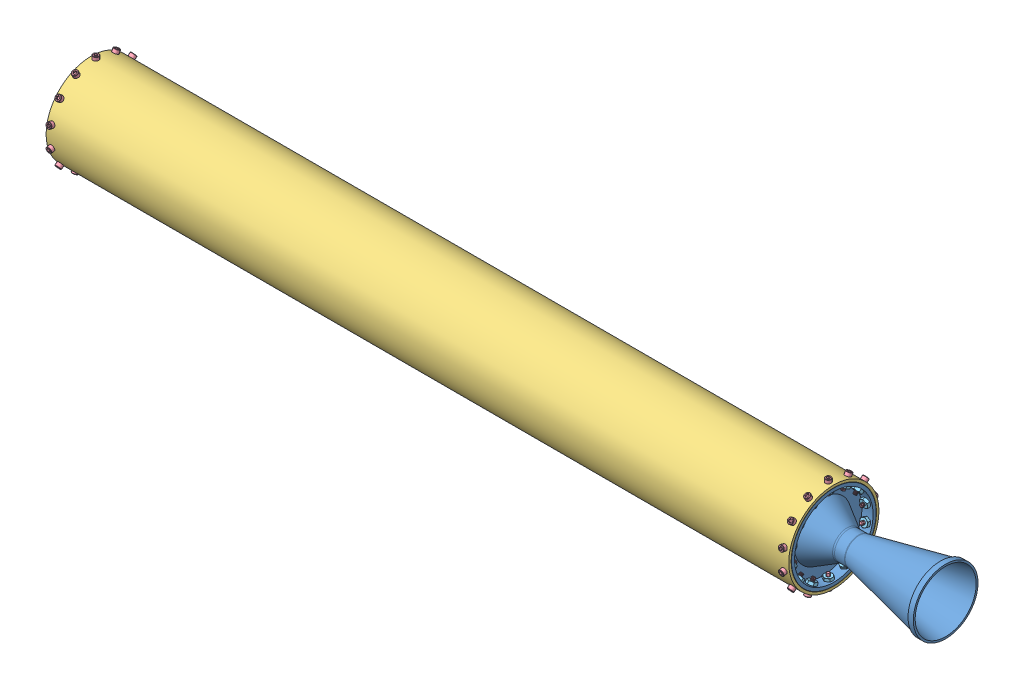
SolidWorks assembly Nakka Lambda Montado, configuration Valor predeterminado. Lengths in mm.
Overall size (702.9 79.69 79.01).
59 component instances, 5 part files, 121 mates.
Components (placement in the parent):
- Nakka Lambda Nozzle Revolucionado-1: Nakka Lambda Nozzle Revolucionado [Valor predeterminado] at (371.1003 28.4053 113.4672) size (113.47 69.52 69.52)
- Nakka Lambda Pressure Bulkhead Revolucionado-1: Nakka Lambda Pressure Bulkhead Revolucionado [Valor predeterminado] at (-252.1521 28.4053 113.4672) size (20.07 69.58 69.58)
- Nakka Lambda Corpo Revolucionado-2: Nakka Lambda Corpo Revolucionado [Valor predeterminado] at (16.4106 28.4053 113.4672) size (610 74 74)
- socket head cap screw_ai440-0375rosca-17: socket head cap screw_ai440-0375rosca [HX-SHCS 0.112-40x0.375x0.375-S] at (336.2613 37.2716 152.313) x (0 -0.222521 -0.974928) z (0.974928 -0.216942 0.049516) size (12.37 4.65 4.65)
- socket head cap screw_ai440-0375rosca-29: socket head cap screw_ai440-0375rosca [HX-SHCS 0.112-40x0.375x0.375-S] at (336.2613 19.539 74.6214) x (0 0.222521 0.974928) z (-0.472254 0.859362 -0.196144) size (12.37 4.65 4.65)
- socket head cap screw_ai440-0375rosca-31: socket head cap screw_ai440-0375rosca [HX-SHCS 0.112-40x0.375x0.375-S] at (336.2613 37.2716 74.6214) x (0 -0.222521 0.974928) z (-0.974928 0.216942 0.049516) size (12.37 4.65 4.65)
- socket head cap screw_ai440-0375rosca-32: socket head cap screw_ai440-0375rosca [HX-SHCS 0.112-40x0.375x0.375-S] at (336.2613 53.2482 82.3153) x (0 -0.62349 0.781831) z (-0.781831 0.487464 0.38874) size (12.37 4.65 4.65)
- socket head cap screw_ai440-0375rosca-33: socket head cap screw_ai440-0375rosca [HX-SHCS 0.112-40x0.375x0.375-S] at (336.2613 64.3043 96.1792) x (0 -0.900969 0.433884) z (-0.433884 0.390916 0.811745) size (12.37 4.65 4.65)
- socket head cap screw_ai440-0375rosca-34: socket head cap screw_ai440-0375rosca [HX-SHCS 0.112-40x0.375x0.375-S] at (336.2613 68.2501 113.4672) x (0 -1 0) z (0 0 1) size (12.37 4.65 4.65)
- socket head cap screw_ai440-0375rosca-35: socket head cap screw_ai440-0375rosca [HX-SHCS 0.112-40x0.375x0.375-S] at (336.2613 64.3043 130.7552) x (0 -0.900969 -0.433884) z (0.433884 -0.390916 0.811745) size (12.37 4.65 4.65)
- socket head cap screw_ai440-0375rosca-36: socket head cap screw_ai440-0375rosca [HX-SHCS 0.112-40x0.375x0.375-S] at (336.2613 53.2482 144.6191) x (0 -0.62349 -0.781831) z (0.781831 -0.487464 0.38874) size (12.37 4.65 4.65)
- socket head cap screw_ai440-0375rosca-37: socket head cap screw_ai440-0375rosca [HX-SHCS 0.112-40x0.375x0.375-S] at (336.2613 19.539 152.313) x (0 0.222521 -0.974928) z (-0.164533 0.961641 0.219488) size (12.37 4.65 4.65)
- socket head cap screw_ai440-0375rosca-38: socket head cap screw_ai440-0375rosca [HX-SHCS 0.112-40x0.375x0.375-S] at (336.2613 3.5625 144.6191) x (0 0.62349 -0.781831) z (0.781831 0.487464 0.38874) size (12.37 4.65 4.65)
- socket head cap screw_ai440-0375rosca-39: socket head cap screw_ai440-0375rosca [HX-SHCS 0.112-40x0.375x0.375-S] at (336.2613 -11.4395 113.4672) x (0 1 0) z (0.020592 0 0.999788) size (12.37 4.65 4.65)
- socket head cap screw_ai440-0375rosca-40: socket head cap screw_ai440-0375rosca [HX-SHCS 0.112-40x0.375x0.375-S] at (336.2613 -7.4936 130.7552) x (0 0.900969 -0.433884) z (0.712028 0.304652 0.632616) size (12.37 4.65 4.65)
- socket head cap screw_ai440-0375rosca-41: socket head cap screw_ai440-0375rosca [HX-SHCS 0.112-40x0.375x0.375-S] at (336.2613 3.5625 82.3153) x (0 0.62349 0.781831) z (-0.781831 -0.487464 0.38874) size (12.37 4.65 4.65)
- socket head cap screw_ai440-0375rosca-42: socket head cap screw_ai440-0375rosca [HX-SHCS 0.112-40x0.375x0.375-S] at (336.2613 -7.4936 96.1792) x (0 0.900969 0.433884) z (-0.433884 -0.390916 0.811745) size (12.37 4.65 4.65)
- socket head cap screw_ai440-0375rosca-44: socket head cap screw_ai440-0375rosca [HX-SHCS 0.112-40x0.375x0.375-S] at (-265.3567 -11.4395 113.4672) x (0 1 0) z (-0.975169 0 0.221462) size (12.37 4.65 4.65)
- socket head cap screw_ai440-0375rosca-45: socket head cap screw_ai440-0375rosca [HX-SHCS 0.112-40x0.375x0.375-S] at (-265.3567 37.2716 152.313) x (0 -0.222521 -0.974928) z (0.974928 -0.216942 0.049516) size (12.37 4.65 4.65)
- socket head cap screw_ai440-0375rosca-46: socket head cap screw_ai440-0375rosca [HX-SHCS 0.112-40x0.375x0.375-S] at (-265.3567 -7.4936 130.7552) x (0 0.900969 -0.433884) z (0.433884 0.390916 0.811745) size (12.37 4.65 4.65)
- socket head cap screw_ai440-0375rosca-47: socket head cap screw_ai440-0375rosca [HX-SHCS 0.112-40x0.375x0.375-S] at (-265.3567 3.5625 144.6191) x (0 0.62349 -0.781831) z (0.223701 -0.762018 -0.607689) size (12.37 4.65 4.65)
- socket head cap screw_ai440-0375rosca-48: socket head cap screw_ai440-0375rosca [HX-SHCS 0.112-40x0.375x0.375-S] at (-265.3567 19.539 152.313) x (0 0.222521 -0.974928) z (-0.073092 0.97232 0.221926) size (12.37 4.65 4.65)
- socket head cap screw_ai440-0375rosca-49: socket head cap screw_ai440-0375rosca [HX-SHCS 0.112-40x0.375x0.375-S] at (-265.3567 68.2501 113.4672) x (0 -1 0) z (0.796271 0 0.60494) size (12.37 4.65 4.65)
- socket head cap screw_ai440-0375rosca-50: socket head cap screw_ai440-0375rosca [HX-SHCS 0.112-40x0.375x0.375-S] at (-265.3567 53.2482 82.3153) x (0 -0.62349 0.781831) z (0.988386 0.11881 0.094748) size (12.37 4.65 4.65)
- socket head cap screw_ai440-0375rosca-58: socket head cap screw_ai440-0375rosca [HX-SHCS 0.112-40x0.375x0.375-S] at (-265.3567 64.3043 130.7552) x (0 -0.900969 -0.433884) z (-0.063272 0.433014 -0.899164) size (12.37 4.65 4.65)
- socket head cap screw_ai440-0375rosca-59: socket head cap screw_ai440-0375rosca [HX-SHCS 0.112-40x0.375x0.375-S] at (-265.3567 64.3043 96.1792) x (0 -0.900969 0.433884) z (-0.99848 0.023912 0.049653) size (12.37 4.65 4.65)
- socket head cap screw_ai440-0375rosca-60: socket head cap screw_ai440-0375rosca [HX-SHCS 0.112-40x0.375x0.375-S] at (-265.3567 53.2482 144.6191) x (0 -0.62349 -0.781831) z (0.332471 0.737356 -0.588022) size (12.37 4.65 4.65)
- socket head cap screw_ai440-0375rosca-61: socket head cap screw_ai440-0375rosca [HX-SHCS 0.112-40x0.375x0.375-S] at (-265.3567 37.2716 74.6214) x (0 -0.222521 0.974928) z (-0.29064 -0.932843 -0.212915) size (12.37 4.65 4.65)
- socket head cap screw_ai440-0375rosca-62: socket head cap screw_ai440-0375rosca [HX-SHCS 0.112-40x0.375x0.375-S] at (-265.3567 19.539 74.6214) x (0 0.222521 0.974928) z (-0.974928 -0.216942 0.049516) size (12.37 4.65 4.65)
- socket head cap screw_ai440-0375rosca-63: socket head cap screw_ai440-0375rosca [HX-SHCS 0.112-40x0.375x0.375-S] at (-265.3567 3.5625 82.3153) x (0 0.62349 0.781831) z (-0.79157 0.47776 -0.381001) size (12.37 4.65 4.65)
- socket head cap screw_ai440-0375rosca-64: socket head cap screw_ai440-0375rosca [HX-SHCS 0.112-40x0.375x0.375-S] at (-265.3567 -7.4936 96.1792) x (0 0.900969 0.433884) z (-0.918204 -0.171864 0.35688) size (12.37 4.65 4.65)
- machine screw nut hex_ai440rosca-4: machine screw nut hex_ai440rosca [MSHXNUT 0.112-40-D-S] at (-265.3567 -1.2873 113.4672) x (0.229119 0 -0.973398) z (0 1 0) size (6.35 7.33 2.49)
- machine screw nut hex_ai440rosca-5: machine screw nut hex_ai440rosca [MSHXNUT 0.112-40-D-S] at (-265.3567 55.1575 100.584) x (1 0 0) z (0 -0.900969 0.433884) size (6.35 7.33 2.49)
- machine screw nut hex_ai440rosca-6: machine screw nut hex_ai440rosca [MSHXNUT 0.112-40-D-S] at (-265.3567 35.0126 84.519) x (1 0 0) z (0 -0.222521 0.974928) size (6.35 7.33 2.49)
- machine screw nut hex_ai440rosca-7: machine screw nut hex_ai440rosca [MSHXNUT 0.112-40-D-S] at (-265.3567 46.9184 90.2526) x (1 0 0) z (0 -0.62349 0.781831) size (6.35 7.33 2.49)
- machine screw nut hex_ai440rosca-8: machine screw nut hex_ai440rosca [MSHXNUT 0.112-40-D-S] at (336.2613 -0.6238 127.4469) x (1 0 0) z (0 -0.900969 0.433884) size (6.35 7.33 2.49)
- machine screw nut hex_ai440rosca-9: machine screw nut hex_ai440rosca [MSHXNUT 0.112-40-D-S] at (336.2613 48.4941 138.6577) x (0.474899 0.688043 -0.548696) z (0 0.62349 0.781831) size (6.35 7.33 2.49)
- machine screw nut hex_ai440rosca-10: machine screw nut hex_ai440rosca [MSHXNUT 0.112-40-D-S] at (336.2613 55.1918 100.5675) x (1 0 0) z (0 -0.900969 0.433884) size (6.35 7.33 2.49)
- machine screw nut hex_ai440rosca-11: machine screw nut hex_ai440rosca [MSHXNUT 0.112-40-D-S] at (-265.3567 35.5665 144.8421) x (0.912832 -0.398097 0.090863) z (0 0.222521 0.974928) size (6.35 7.33 2.49)
- machine screw nut hex_ai440rosca-12: machine screw nut hex_ai440rosca [MSHXNUT 0.112-40-D-S] at (-265.3567 9.8923 90.2526) x (1 0 0) z (0 0.62349 0.781831) size (6.35 7.33 2.49)
- machine screw nut hex_ai440rosca-13: machine screw nut hex_ai440rosca [MSHXNUT 0.112-40-D-S] at (336.2613 21.2357 144.8793) x (0.004219 -0.974919 -0.222519) z (0 -0.222521 0.974928) size (6.35 7.33 2.49)
- machine screw nut hex_ai440rosca-14: machine screw nut hex_ai440rosca [MSHXNUT 0.112-40-D-S] at (-265.3567 48.4704 138.6279) x (0.052973 -0.780734 0.622614) z (0 0.62349 0.781831) size (6.35 7.33 2.49)
- machine screw nut hex_ai440rosca-15: machine screw nut hex_ai440rosca [MSHXNUT 0.112-40-D-S] at (336.2613 35.5749 144.8793) x (-0.28602 0.934199 -0.213225) z (0 0.222521 0.974928) size (6.35 7.33 2.49)
- machine screw nut hex_ai440rosca-16: machine screw nut hex_ai440rosca [MSHXNUT 0.112-40-D-S] at (-265.3567 8.3403 138.6279) x (0.580628 -0.636543 -0.507626) z (0 -0.62349 0.781831) size (6.35 7.33 2.49)
- machine screw nut hex_ai440rosca-17: machine screw nut hex_ai440rosca [MSHXNUT 0.112-40-D-S] at (336.2613 9.8686 90.2228) x (1 0 0) z (0 0.62349 0.781831) size (6.35 7.33 2.49)
- machine screw nut hex_ai440rosca-18: machine screw nut hex_ai440rosca [MSHXNUT 0.112-40-D-S] at (336.2613 8.3166 138.6577) x (0.295846 -0.746833 -0.59558) z (0 -0.62349 0.781831) size (6.35 7.33 2.49)
- machine screw nut hex_ai440rosca-19: machine screw nut hex_ai440rosca [MSHXNUT 0.112-40-D-S] at (336.2613 58.136 113.4672) x (0.879271 0 -0.476321) z (0 -1 0) size (6.35 7.33 2.49)
- machine screw nut hex_ai440rosca-20: machine screw nut hex_ai440rosca [MSHXNUT 0.112-40-D-S] at (336.2613 1.6189 100.5675) x (1 0 0) z (0 0.900969 0.433884) size (6.35 7.33 2.49)
- machine screw nut hex_ai440rosca-21: machine screw nut hex_ai440rosca [MSHXNUT 0.112-40-D-S] at (336.2613 57.4345 127.4469) x (-0.189494 -0.426023 0.884645) z (0 0.900969 0.433884) size (6.35 7.33 2.49)
- machine screw nut hex_ai440rosca-22: machine screw nut hex_ai440rosca [MSHXNUT 0.112-40-D-S] at (336.2613 -1.3254 113.4672) x (1 0 0) z (0 1 0) size (6.35 7.33 2.49)
- machine screw nut hex_ai440rosca-23: machine screw nut hex_ai440rosca [MSHXNUT 0.112-40-D-S] at (336.2613 46.9421 90.2228) x (1 0 0) z (0 -0.62349 0.781831) size (6.35 7.33 2.49)
- machine screw nut hex_ai440rosca-24: machine screw nut hex_ai440rosca [MSHXNUT 0.112-40-D-S] at (336.2613 21.7896 84.4819) x (1 0 0) z (0 0.222521 0.974928) size (6.35 7.33 2.49)
- machine screw nut hex_ai440rosca-25: machine screw nut hex_ai440rosca [MSHXNUT 0.112-40-D-S] at (336.2613 35.021 84.4819) x (1 0 0) z (0 -0.222521 0.974928) size (6.35 7.33 2.49)
- machine screw nut hex_ai440rosca-26: machine screw nut hex_ai440rosca [MSHXNUT 0.112-40-D-S] at (-265.3567 58.0979 113.4672) x (1 0 0) z (0 -1 0) size (6.35 7.33 2.49)
- machine screw nut hex_ai440rosca-27: machine screw nut hex_ai440rosca [MSHXNUT 0.112-40-D-S] at (-265.3567 21.2442 144.8421) x (-0.080248 -0.971784 -0.221803) z (0 -0.222521 0.974928) size (6.35 7.33 2.49)
- machine screw nut hex_ai440rosca-28: machine screw nut hex_ai440rosca [MSHXNUT 0.112-40-D-S] at (-265.3567 21.7981 84.519) x (1 0 0) z (0 0.222521 0.974928) size (6.35 7.33 2.49)
- machine screw nut hex_ai440rosca-29: machine screw nut hex_ai440rosca [MSHXNUT 0.112-40-D-S] at (-265.3567 -0.5895 127.4303) x (-0.019937 -0.433797 -0.90079) z (0 -0.900969 0.433884) size (6.35 7.33 2.49)
- machine screw nut hex_ai440rosca-33: machine screw nut hex_ai440rosca [MSHXNUT 0.112-40-D-S] at (-265.3567 57.4001 127.4303) x (0.879954 -0.20612 0.428013) z (0 0.900969 0.433884) size (6.35 7.33 2.49)
- machine screw nut hex_ai440rosca-32: machine screw nut hex_ai440rosca [MSHXNUT 0.112-40-D-S] at (-265.3567 1.6532 100.584) x (1 0 0) z (0 0.900969 0.433884) size (6.35 7.33 2.49)
Mates (geometry in assembly coordinates):
- Concêntrico2: concentric aligned: circle of Nakka Lambda Nozzle Revolucionado-1; circle of Nakka Lambda Corpo Revolucionado-2
- Concêntrico7: concentric aligned: cylinder of Nakka Lambda Pressure Bulkhead Revolucionado-1 through (-265.3567 -2.8779 128.5324) axis (0 -0.900969 0.433884) radius 1.1303; cylinder of Nakka Lambda Corpo Revolucionado-2 through (-265.3567 -4.9305 129.5209) axis (0 -0.900969 0.433884) radius 1.1303
- Concêntrico22: concentric aligned: cylinder of Nakka Lambda Corpo Revolucionado-2 through (336.2613 36.6386 149.5395) axis (0 0.222521 0.974928) radius 1.1303; cylinder of socket head cap screw_ai440-0375rosca-17 through (336.2613 44.3367 183.267) axis (0 0.222521 0.974928) radius 1.4224
- Concêntrico25: concentric aligned: cylinder of Nakka Lambda Nozzle Revolucionado-1 through (336.2613 50.0778 140.6436) axis (0 0.62349 0.781831) radius 1.1303; cylinder of Nakka Lambda Corpo Revolucionado-2 through (336.2613 51.4745 142.3949) axis (0 0.62349 0.781831) radius 1.1303
- Concêntrico26: concentric aligned: cylinder of Nakka Lambda Nozzle Revolucionado-1 through (336.2613 36.1402 147.3556) axis (0 0.222521 0.974928) radius 1.1303; cylinder of Nakka Lambda Corpo Revolucionado-2 through (336.2613 36.6386 149.5395) axis (0 0.222521 0.974928) radius 1.1303
- Concêntrico27: concentric aligned: circle of Nakka Lambda Nozzle Revolucionado-1; circle of Nakka Lambda Corpo Revolucionado-2
- Tangente12: tangent anti-aligned: cylinder of Nakka Lambda Corpo Revolucionado-2 through (-269.1667 28.4053 113.4672) axis (-1 0 0) radius 37; plane of socket head cap screw_ai440-0375rosca-17 through (336.7785 38.8476 149.0353) normal (0 -0.222521 -0.974928)
- Concêntrico34: concentric aligned: cylinder of Nakka Lambda Nozzle Revolucionado-1 through (336.2613 -2.9122 98.3854) axis (0 -0.900969 -0.433884) radius 1.1303; cylinder of Nakka Lambda Corpo Revolucionado-2 through (336.2613 -4.9305 97.4135) axis (0 -0.900969 -0.433884) radius 1.1303
- Concêntrico54: concentric aligned: cylinder of Nakka Lambda Nozzle Revolucionado-1 through (336.2613 50.0778 140.6436) axis (0 0.62349 0.781831) radius 1.1303; cylinder of Nakka Lambda Corpo Revolucionado-2 through (336.2613 51.4745 142.3949) axis (0 0.62349 0.781831) radius 1.1303
- Concêntrico57: concentric aligned: cylinder of Nakka Lambda Corpo Revolucionado-2 through (336.2613 20.1721 77.3948) axis (0 -0.222521 -0.974928) radius 1.1303; cylinder of socket head cap screw_ai440-0375rosca-29 through (336.2613 12.474 43.6674) axis (0 -0.222521 -0.974928) radius 1.4224
- Tangente14: tangent anti-aligned: cylinder of Nakka Lambda Corpo Revolucionado-2 through (-269.1667 28.4053 113.4672) axis (-1 0 0) radius 37; plane of socket head cap screw_ai440-0375rosca-29 through (338.3099 21.2421 77.1506) normal (0 0.222521 0.974928)
- Concêntrico60: concentric aligned: cylinder of Nakka Lambda Corpo Revolucionado-2 through (336.2613 36.6386 77.3948) axis (0 0.222521 -0.974928) radius 1.1303; cylinder of socket head cap screw_ai440-0375rosca-31 through (336.2613 44.3367 43.6674) axis (0 0.222521 -0.974928) radius 1.4224
- Tangente15: tangent anti-aligned: cylinder of Nakka Lambda Corpo Revolucionado-2 through (-269.1667 28.4053 113.4672) axis (-1 0 0) radius 37; plane of socket head cap screw_ai440-0375rosca-31 through (336.7785 38.8476 77.899) normal (0 -0.222521 0.974928)
- Concêntrico62: concentric aligned: cylinder of Nakka Lambda Corpo Revolucionado-2 through (336.2613 51.4745 84.5394) axis (0 0.62349 -0.781831) radius 1.1303; cylinder of socket head cap screw_ai440-0375rosca-32 through (336.2613 73.044 57.4921) axis (0 0.62349 -0.781831) radius 1.4224
- Tangente17: tangent anti-aligned: cylinder of Nakka Lambda Corpo Revolucionado-2 through (-269.1667 28.4053 113.4672) axis (-1 0 0) radius 37; plane of socket head cap screw_ai440-0375rosca-32 through (337.7104 52.8951 85.6723) normal (0 -0.62349 0.781831)
- Concêntrico64: concentric aligned: cylinder of Nakka Lambda Corpo Revolucionado-2 through (336.2613 61.7412 97.4135) axis (0 0.900969 -0.433884) radius 1.1303; cylinder of socket head cap screw_ai440-0375rosca-33 through (336.2613 92.91 82.4034) axis (0 0.900969 -0.433884) radius 1.4224
- Tangente18: tangent anti-aligned: cylinder of Nakka Lambda Corpo Revolucionado-2 through (-269.1667 28.4053 113.4672) axis (-1 0 0) radius 37; plane of socket head cap screw_ai440-0375rosca-33 through (338.3553 62.1787 98.322) normal (0 -0.900969 0.433884)
- Concêntrico66: concentric aligned: cylinder of Nakka Lambda Corpo Revolucionado-2 through (336.2613 65.4053 113.4672) axis (0 1 0) radius 1.1303; cylinder of socket head cap screw_ai440-0375rosca-34 through (336.2613 100.0001 113.4672) axis (0 1 0) radius 1.4224
- Tangente19: tangent anti-aligned: cylinder of Nakka Lambda Corpo Revolucionado-2 through (-269.1667 28.4053 113.4672) axis (-1 0 0) radius 37; plane of socket head cap screw_ai440-0375rosca-34 through (338.5854 65.4053 113.4672) normal (0 -1 0)
- Concêntrico68: concentric aligned: cylinder of Nakka Lambda Corpo Revolucionado-2 through (336.2613 61.7412 129.5209) axis (0 0.900969 0.433884) radius 1.1303; cylinder of socket head cap screw_ai440-0375rosca-35 through (336.2613 92.91 144.531) axis (0 0.900969 0.433884) radius 1.4224
- Tangente20: tangent anti-aligned: cylinder of Nakka Lambda Corpo Revolucionado-2 through (-269.1667 28.4053 113.4672) axis (-1 0 0) radius 37; plane of socket head cap screw_ai440-0375rosca-35 through (338.3553 62.1787 128.6124) normal (0 -0.900969 -0.433884)
- Concêntrico70: concentric aligned: cylinder of Nakka Lambda Corpo Revolucionado-2 through (336.2613 51.4745 142.3949) axis (0 0.62349 0.781831) radius 1.1303; cylinder of socket head cap screw_ai440-0375rosca-36 through (336.2613 73.044 169.4422) axis (0 0.62349 0.781831) radius 1.4224
- Tangente21: tangent anti-aligned: cylinder of Nakka Lambda Corpo Revolucionado-2 through (-269.1667 28.4053 113.4672) axis (-1 0 0) radius 37; plane of socket head cap screw_ai440-0375rosca-36 through (337.7104 52.8951 141.262) normal (0 -0.62349 -0.781831)
- Concêntrico72: concentric aligned: cylinder of Nakka Lambda Corpo Revolucionado-2 through (336.2613 20.1721 149.5395) axis (0 -0.222521 0.974928) radius 1.1303; cylinder of socket head cap screw_ai440-0375rosca-37 through (336.2613 12.474 183.267) axis (0 -0.222521 0.974928) radius 1.4224
- Tangente22: tangent anti-aligned: cylinder of Nakka Lambda Corpo Revolucionado-2 through (-269.1667 28.4053 113.4672) axis (-1 0 0) radius 37; plane of socket head cap screw_ai440-0375rosca-37 through (333.9689 19.7993 149.4544) normal (0 0.222521 -0.974928)
- Concêntrico76: concentric aligned: cylinder of Nakka Lambda Corpo Revolucionado-2 through (336.2613 5.3362 142.3949) axis (0 -0.62349 0.781831) radius 1.1303; cylinder of socket head cap screw_ai440-0375rosca-38 through (336.2613 -16.2333 169.4422) axis (0 -0.62349 0.781831) radius 1.4224
- Tangente23: tangent anti-aligned: cylinder of Nakka Lambda Corpo Revolucionado-2 through (-269.1667 28.4053 113.4672) axis (-1 0 0) radius 37; plane of socket head cap screw_ai440-0375rosca-38 through (334.8123 6.7569 143.5279) normal (0 0.62349 -0.781831)
- Concêntrico78: concentric aligned: cylinder of Nakka Lambda Corpo Revolucionado-2 through (336.2613 -4.9305 129.5209) axis (0 -0.900969 0.433884) radius 1.1303; cylinder of socket head cap screw_ai440-0375rosca-40 through (336.2613 -36.0993 144.531) axis (0 -0.900969 0.433884) radius 1.4224
- Tangente24: tangent anti-aligned: cylinder of Nakka Lambda Corpo Revolucionado-2 through (-269.1667 28.4053 113.4672) axis (-1 0 0) radius 37; plane of socket head cap screw_ai440-0375rosca-40 through (334.6294 -4.2125 131.0118) normal (0 0.900969 -0.433884)
- Concêntrico80: concentric aligned: cylinder of Nakka Lambda Corpo Revolucionado-2 through (336.2613 -8.5947 113.4672) axis (0 -1 0) radius 1.1303; cylinder of socket head cap screw_ai440-0375rosca-39 through (336.2613 -43.1895 113.4672) axis (0 -1 0) radius 1.4224
- Tangente25: tangent anti-aligned: cylinder of Nakka Lambda Corpo Revolucionado-2 through (-269.1667 28.4053 113.4672) axis (-1 0 0) radius 37; plane of socket head cap screw_ai440-0375rosca-39 through (333.9377 -8.5947 113.515) normal (0 1 0)
- Concêntrico81: concentric aligned: circle of Nakka Lambda Pressure Bulkhead Revolucionado-1; circle of Nakka Lambda Corpo Revolucionado-2
- Concêntrico83: concentric aligned: cylinder of Nakka Lambda Corpo Revolucionado-2 through (336.2613 -4.9305 97.4135) axis (0 -0.900969 -0.433884) radius 1.1303; cylinder of socket head cap screw_ai440-0375rosca-42 through (336.2613 -36.0993 82.4034) axis (0 -0.900969 -0.433884) radius 1.4224
- Tangente26: tangent anti-aligned: cylinder of Nakka Lambda Corpo Revolucionado-2 through (-269.1667 28.4053 113.4672) axis (-1 0 0) radius 37; plane of socket head cap screw_ai440-0375rosca-42 through (334.1674 -4.493 96.505) normal (0 0.900969 0.433884)
- Concêntrico85: concentric aligned: cylinder of Nakka Lambda Corpo Revolucionado-2 through (336.2613 5.3362 84.5394) axis (0 -0.62349 -0.781831) radius 1.1303; cylinder of socket head cap screw_ai440-0375rosca-41 through (336.2613 -16.2333 57.4921) axis (0 -0.62349 -0.781831) radius 1.4224
- Tangente27: tangent anti-aligned: cylinder of Nakka Lambda Corpo Revolucionado-2 through (-269.1667 28.4053 113.4672) axis (-1 0 0) radius 37; plane of socket head cap screw_ai440-0375rosca-41 through (334.8123 6.7569 83.4065) normal (0 0.62349 0.781831)
- Concêntrico86: concentric aligned: cylinder of Nakka Lambda Pressure Bulkhead Revolucionado-1 through (-265.3567 20.679 79.6159) axis (0 -0.222521 -0.974928) radius 1.1303; cylinder of Nakka Lambda Corpo Revolucionado-2 through (-265.3567 20.1721 77.3948) axis (0 -0.222521 -0.974928) radius 1.1303
- Concêntrico88: concentric aligned: cylinder of Nakka Lambda Corpo Revolucionado-2 through (-265.3567 -8.5947 113.4672) axis (0 -1 0) radius 1.1303; cylinder of socket head cap screw_ai440-0375rosca-44 through (-265.3567 -43.1895 113.4672) axis (0 -1 0) radius 1.4224
- Tangente28: tangent anti-aligned: cylinder of Nakka Lambda Corpo Revolucionado-2 through (-269.1667 28.4053 113.4672) axis (-1 0 0) radius 37; plane of socket head cap screw_ai440-0375rosca-44 through (-265.8714 -8.5947 111.2008) normal (0 1 0)
- Concêntrico90: concentric aligned: cylinder of Nakka Lambda Corpo Revolucionado-2 through (-265.3567 -4.9305 129.5209) axis (0 -0.900969 0.433884) radius 1.1303; cylinder of socket head cap screw_ai440-0375rosca-46 through (-265.3567 -36.0993 144.531) axis (0 -0.900969 0.433884) radius 1.4224
- Tangente29: tangent anti-aligned: cylinder of Nakka Lambda Corpo Revolucionado-2 through (-269.1667 28.4053 113.4672) axis (-1 0 0) radius 37; plane of socket head cap screw_ai440-0375rosca-46 through (-267.4506 -4.493 130.4294) normal (0 0.900969 -0.433884)
- Concêntrico92: concentric aligned: cylinder of Nakka Lambda Corpo Revolucionado-2 through (-265.3567 5.3362 142.3949) axis (0 -0.62349 0.781831) radius 1.1303; cylinder of socket head cap screw_ai440-0375rosca-47 through (-265.3567 -16.2333 169.4422) axis (0 -0.62349 0.781831) radius 1.4224
- Tangente30: tangent anti-aligned: cylinder of Nakka Lambda Corpo Revolucionado-2 through (-269.1667 28.4053 113.4672) axis (-1 0 0) radius 37; plane of socket head cap screw_ai440-0375rosca-47 through (-263.0915 5.7427 142.7191) normal (0 0.62349 -0.781831)
- Concêntrico94: concentric aligned: cylinder of Nakka Lambda Corpo Revolucionado-2 through (-265.3567 20.1721 149.5395) axis (0 -0.222521 0.974928) radius 1.1303; cylinder of socket head cap screw_ai440-0375rosca-48 through (-265.3567 12.474 183.267) axis (0 -0.222521 0.974928) radius 1.4224
- Tangente31: tangent anti-aligned: cylinder of Nakka Lambda Corpo Revolucionado-2 through (-269.1667 28.4053 113.4672) axis (-1 0 0) radius 37; plane of socket head cap screw_ai440-0375rosca-48 through (-267.6746 20.0065 149.5017) normal (0 0.222521 -0.974928)
- Concêntrico96: concentric aligned: cylinder of Nakka Lambda Corpo Revolucionado-2 through (-265.3567 36.6386 149.5395) axis (0 0.222521 0.974928) radius 1.1303; cylinder of socket head cap screw_ai440-0375rosca-45 through (-265.3567 44.3367 183.267) axis (0 0.222521 0.974928) radius 1.4224
- Tangente32: tangent anti-aligned: cylinder of Nakka Lambda Corpo Revolucionado-2 through (-269.1667 28.4053 113.4672) axis (-1 0 0) radius 37; plane of socket head cap screw_ai440-0375rosca-45 through (-264.8395 38.8476 149.0353) normal (0 -0.222521 -0.974928)
- Concêntrico98: concentric aligned: cylinder of Nakka Lambda Corpo Revolucionado-2 through (-265.3567 51.4745 142.3949) axis (0 0.62349 0.781831) radius 1.1303; cylinder of socket head cap screw_ai440-0375rosca-60 through (-265.3567 73.044 169.4422) axis (0 0.62349 0.781831) radius 1.4224
- Tangente33: tangent anti-aligned: cylinder of Nakka Lambda Corpo Revolucionado-2 through (-269.1667 28.4053 113.4672) axis (-1 0 0) radius 37; plane of socket head cap screw_ai440-0375rosca-60 through (-267.5486 52.0786 141.9132) normal (0 -0.62349 -0.781831)
- Concêntrico100: concentric aligned: cylinder of Nakka Lambda Corpo Revolucionado-2 through (-265.3567 61.7412 129.5209) axis (0 0.900969 0.433884) radius 1.1303; cylinder of socket head cap screw_ai440-0375rosca-58 through (-265.3567 92.91 144.531) axis (0 0.900969 0.433884) radius 1.4224
- Tangente34: tangent anti-aligned: cylinder of Nakka Lambda Corpo Revolucionado-2 through (-269.1667 28.4053 113.4672) axis (-1 0 0) radius 37; plane of socket head cap screw_ai440-0375rosca-58 through (-267.6761 61.6774 129.6534) normal (0 -0.900969 -0.433884)
- Concêntrico102: concentric aligned: cylinder of Nakka Lambda Corpo Revolucionado-2 through (-265.3567 65.4053 113.4672) axis (0 1 0) radius 1.1303; cylinder of socket head cap screw_ai440-0375rosca-49 through (-265.3567 100.0001 113.4672) axis (0 1 0) radius 1.4224
- Tangente35: tangent anti-aligned: cylinder of Nakka Lambda Corpo Revolucionado-2 through (-269.1667 28.4053 113.4672) axis (-1 0 0) radius 37; plane of socket head cap screw_ai440-0375rosca-49 through (-263.9507 65.4053 111.6166) normal (0 -1 0)
- Concêntrico104: concentric aligned: cylinder of Nakka Lambda Corpo Revolucionado-2 through (-265.3567 61.7412 97.4135) axis (0 0.900969 -0.433884) radius 1.1303; cylinder of socket head cap screw_ai440-0375rosca-59 through (-265.3567 92.91 82.4034) axis (0 0.900969 -0.433884) radius 1.4224
- Tangente36: tangent anti-aligned: cylinder of Nakka Lambda Corpo Revolucionado-2 through (-269.1667 28.4053 113.4672) axis (-1 0 0) radius 37; plane of socket head cap screw_ai440-0375rosca-59 through (-265.2286 62.7481 99.5042) normal (0 -0.900969 0.433884)
- Concêntrico106: concentric aligned: cylinder of Nakka Lambda Corpo Revolucionado-2 through (-265.3567 51.4745 84.5394) axis (0 0.62349 -0.781831) radius 1.1303; cylinder of socket head cap screw_ai440-0375rosca-50 through (-265.3567 73.044 57.4921) axis (0 0.62349 -0.781831) radius 1.4224
- Tangente37: tangent anti-aligned: cylinder of Nakka Lambda Corpo Revolucionado-2 through (-269.1667 28.4053 113.4672) axis (-1 0 0) radius 37; plane of socket head cap screw_ai440-0375rosca-50 through (-265.0035 49.6785 83.1072) normal (0 -0.62349 0.781831)
- Concêntrico108: concentric aligned: cylinder of Nakka Lambda Corpo Revolucionado-2 through (-265.3567 36.6386 77.3948) axis (0 0.222521 -0.974928) radius 1.1303; cylinder of socket head cap screw_ai440-0375rosca-61 through (-265.3567 44.3367 43.6674) axis (0 0.222521 -0.974928) radius 1.4224
- Tangente38: tangent anti-aligned: cylinder of Nakka Lambda Corpo Revolucionado-2 through (-269.1667 28.4053 113.4672) axis (-1 0 0) radius 37; plane of socket head cap screw_ai440-0375rosca-61 through (-267.5805 37.2972 77.5452) normal (0 -0.222521 0.974928)
- Concêntrico110: concentric aligned: cylinder of Nakka Lambda Corpo Revolucionado-2 through (-265.3567 20.1721 77.3948) axis (0 -0.222521 -0.974928) radius 1.1303; cylinder of socket head cap screw_ai440-0375rosca-62 through (-265.3567 12.474 43.6674) axis (0 -0.222521 -0.974928) radius 1.4224
- Tangente39: tangent anti-aligned: cylinder of Nakka Lambda Corpo Revolucionado-2 through (-269.1667 28.4053 113.4672) axis (-1 0 0) radius 37; plane of socket head cap screw_ai440-0375rosca-62 through (-265.8738 22.3811 76.8907) normal (0 0.222521 0.974928)
- Concêntrico112: concentric aligned: cylinder of Nakka Lambda Corpo Revolucionado-2 through (-265.3567 5.3362 84.5394) axis (0 -0.62349 -0.781831) radius 1.1303; cylinder of socket head cap screw_ai440-0375rosca-63 through (-265.3567 -16.2333 57.4921) axis (0 -0.62349 -0.781831) radius 1.4224
- Tangente40: tangent anti-aligned: cylinder of Nakka Lambda Corpo Revolucionado-2 through (-269.1667 28.4053 113.4672) axis (-1 0 0) radius 37; plane of socket head cap screw_ai440-0375rosca-63 through (-263.9365 6.7745 83.3924) normal (0 0.62349 0.781831)
- Concêntrico114: concentric aligned: cylinder of Nakka Lambda Corpo Revolucionado-2 through (-265.3567 -4.9305 97.4135) axis (0 -0.900969 -0.433884) radius 1.1303; cylinder of socket head cap screw_ai440-0375rosca-64 through (-265.3567 -36.0993 82.4034) axis (0 -0.900969 -0.433884) radius 1.4224
- Tangente42: tangent anti-aligned: cylinder of Nakka Lambda Corpo Revolucionado-2 through (-269.1667 28.4053 113.4672) axis (-1 0 0) radius 37; plane of socket head cap screw_ai440-0375rosca-64 through (-266.2773 -4.0046 95.4908) normal (0 0.900969 0.433884)
- Concêntrico117: concentric anti-aligned: cylinder of socket head cap screw_ai440-0375rosca-31 through (336.2613 44.3367 43.6674) axis (0 0.222521 -0.974928) radius 1.4224; cylinder of machine screw nut hex_ai440rosca-25 through (336.2613 35.5749 82.0551) axis (0 -0.222521 0.974928) radius 1.1303
- Tangente46: tangent aligned: cylinder of Nakka Lambda Nozzle Revolucionado-1 through (319.2433 28.4053 113.4672) axis (-1 0 0) radius 32.2199; plane of machine screw nut hex_ai440rosca-25 through (336.2613 39.1492 82.8709) normal (0 0.222521 -0.974928)
- Concêntrico118: concentric anti-aligned: cylinder of socket head cap screw_ai440-0375rosca-32 through (336.2613 73.044 57.4921) axis (0 0.62349 -0.781831) radius 1.4224; cylinder of machine screw nut hex_ai440rosca-23 through (336.2613 48.4941 88.2766) axis (0 -0.62349 0.781831) radius 1.1303
- Tangente47: tangent aligned: cylinder of Nakka Lambda Nozzle Revolucionado-1 through (319.2433 28.4053 113.4672) axis (-1 0 0) radius 32.2199; plane of machine screw nut hex_ai440rosca-23 through (336.2613 51.3605 90.5625) normal (0 0.62349 -0.781831)
- Concêntrico119: concentric anti-aligned: cylinder of socket head cap screw_ai440-0375rosca-29 through (336.2613 12.474 43.6674) axis (0 -0.222521 -0.974928) radius 1.4224; cylinder of machine screw nut hex_ai440rosca-24 through (336.2613 21.2357 82.0551) axis (0 0.222521 0.974928) radius 1.1303
- Tangente48: tangent aligned: cylinder of Nakka Lambda Nozzle Revolucionado-1 through (319.2433 28.4053 113.4672) axis (-1 0 0) radius 32.2199; plane of machine screw nut hex_ai440rosca-24 through (336.2613 24.81 81.2393) normal (0 -0.222521 -0.974928)
- Concêntrico120: concentric anti-aligned: cylinder of socket head cap screw_ai440-0375rosca-33 through (336.2613 92.91 82.4034) axis (0 0.900969 -0.433884) radius 1.4224; cylinder of machine screw nut hex_ai440rosca-10 through (336.2613 57.4345 99.4875) axis (0 -0.900969 0.433884) radius 1.1303
- Tangente49: tangent aligned: cylinder of Nakka Lambda Nozzle Revolucionado-1 through (319.2433 28.4053 113.4672) axis (-1 0 0) radius 32.2199; plane of machine screw nut hex_ai440rosca-10 through (336.2613 59.0252 102.7906) normal (0 0.900969 -0.433884)
- Concêntrico122: concentric anti-aligned: cylinder of socket head cap screw_ai440-0375rosca-39 through (336.2613 -43.1895 113.4672) axis (0 -1 0) radius 1.4224; cylinder of machine screw nut hex_ai440rosca-22 through (336.2613 -3.8146 113.4672) axis (0 1 0) radius 1.1303
- Tangente52: tangent aligned: cylinder of Nakka Lambda Nozzle Revolucionado-1 through (319.2433 28.4053 113.4672) axis (-1 0 0) radius 32.2199; plane of machine screw nut hex_ai440rosca-22 through (336.2613 -3.8146 109.801) normal (0 -1 0)
- Concêntrico123: concentric anti-aligned: cylinder of socket head cap screw_ai440-0375rosca-42 through (336.2613 -36.0993 82.4034) axis (0 -0.900969 -0.433884) radius 1.4224; cylinder of machine screw nut hex_ai440rosca-20 through (336.2613 -0.6238 99.4875) axis (0 0.900969 0.433884) radius 1.1303
- Tangente53: tangent aligned: cylinder of Nakka Lambda Nozzle Revolucionado-1 through (319.2433 28.4053 113.4672) axis (-1 0 0) radius 32.2199; plane of machine screw nut hex_ai440rosca-20 through (336.2613 0.9669 96.1844) normal (0 -0.900969 -0.433884)
- Concêntrico127: concentric aligned: cylinder of socket head cap screw_ai440-0375rosca-40 through (336.2613 -36.0993 144.531) axis (0 -0.900969 0.433884) radius 1.4224; cylinder of machine screw nut hex_ai440rosca-8 through (336.2613 1.6189 126.3668) axis (0 -0.900969 0.433884) radius 1.1303
- Tangente55: tangent aligned: cylinder of Nakka Lambda Nozzle Revolucionado-1 through (319.2433 28.4053 113.4672) axis (-1 0 0) radius 32.2199; plane of machine screw nut hex_ai440rosca-8 through (336.2613 0.9669 130.75) normal (0 -0.900969 0.433884)
- Concêntrico128: concentric anti-aligned: cylinder of socket head cap screw_ai440-0375rosca-34 through (336.2613 100.0001 113.4672) axis (0 1 0) radius 1.4224; cylinder of machine screw nut hex_ai440rosca-19 through (336.2613 60.6252 113.4672) axis (0 -1 0) radius 1.1303
- Tangente57: tangent aligned: cylinder of Nakka Lambda Nozzle Revolucionado-1 through (319.2433 28.4053 113.4672) axis (-1 0 0) radius 32.2199; plane of machine screw nut hex_ai440rosca-19 through (338.0076 60.6252 116.6907) normal (0 1 0)
- Concêntrico129: concentric aligned: cylinder of socket head cap screw_ai440-0375rosca-38 through (336.2613 -16.2333 169.4422) axis (0 -0.62349 0.781831) radius 1.4224; cylinder of machine screw nut hex_ai440rosca-18 through (336.2613 9.8686 136.7116) axis (0 -0.62349 0.781831) radius 1.1303
- Tangente58: tangent aligned: cylinder of Nakka Lambda Nozzle Revolucionado-1 through (319.2433 28.4053 113.4672) axis (-1 0 0) radius 32.2199; plane of machine screw nut hex_ai440rosca-18 through (339.7634 9.1646 139.334) normal (0 -0.62349 0.781831)
- Concêntrico130: concentric aligned: cylinder of socket head cap screw_ai440-0375rosca-37 through (336.2613 12.474 183.267) axis (0 -0.222521 0.974928) radius 1.4224; cylinder of machine screw nut hex_ai440rosca-13 through (336.2613 21.7896 142.4525) axis (0 -0.222521 0.974928) radius 1.1303
- Tangente59: tangent aligned: cylinder of Nakka Lambda Nozzle Revolucionado-1 through (319.2433 28.4053 113.4672) axis (-1 0 0) radius 32.2199; plane of machine screw nut hex_ai440rosca-13 through (339.9275 21.2508 144.8827) normal (0 -0.222521 0.974928)
- Concêntrico131: concentric anti-aligned: cylinder of socket head cap screw_ai440-0375rosca-41 through (336.2613 -16.2333 57.4921) axis (0 -0.62349 -0.781831) radius 1.4224; cylinder of machine screw nut hex_ai440rosca-17 through (336.2613 8.3166 88.2766) axis (0 0.62349 0.781831) radius 1.1303
- Tangente60: tangent aligned: cylinder of Nakka Lambda Nozzle Revolucionado-1 through (319.2433 28.4053 113.4672) axis (-1 0 0) radius 32.2199; plane of machine screw nut hex_ai440rosca-17 through (336.2613 11.1829 85.9908) normal (0 -0.62349 -0.781831)
- Concêntrico132: concentric aligned: cylinder of socket head cap screw_ai440-0375rosca-17 through (336.2613 44.3367 183.267) axis (0 0.222521 0.974928) radius 1.4224; cylinder of machine screw nut hex_ai440rosca-15 through (336.2613 35.021 142.4525) axis (0 0.222521 0.974928) radius 1.1303
- Tangente61: tangent aligned: cylinder of Nakka Lambda Nozzle Revolucionado-1 through (319.2433 28.4053 113.4672) axis (-1 0 0) radius 32.2199; plane of machine screw nut hex_ai440rosca-15 through (332.7483 34.5526 145.1126) normal (0 0.222521 0.974928)
- Concêntrico133: concentric aligned: cylinder of socket head cap screw_ai440-0375rosca-35 through (336.2613 92.91 144.531) axis (0 0.900969 0.433884) radius 1.4224; cylinder of machine screw nut hex_ai440rosca-21 through (336.2613 55.1918 126.3668) axis (0 0.900969 0.433884) radius 1.1303
- Tangente62: tangent aligned: cylinder of Nakka Lambda Nozzle Revolucionado-1 through (319.2433 28.4053 113.4672) axis (-1 0 0) radius 32.2199; plane of machine screw nut hex_ai440rosca-21 through (339.8611 57.133 128.0728) normal (0 0.900969 0.433884)
- Concêntrico134: concentric aligned: cylinder of socket head cap screw_ai440-0375rosca-36 through (336.2613 73.044 169.4422) axis (0 0.62349 0.781831) radius 1.4224; cylinder of machine screw nut hex_ai440rosca-9 through (336.2613 46.9421 136.7116) axis (0 0.62349 0.781831) radius 1.1303
- Tangente63: tangent aligned: cylinder of Nakka Lambda Nozzle Revolucionado-1 through (319.2433 28.4053 113.4672) axis (-1 0 0) radius 32.2199; plane of machine screw nut hex_ai440rosca-9 through (333.0349 49.8553 137.5722) normal (0 0.62349 0.781831)
- Concêntrico135: concentric anti-aligned: cylinder of socket head cap screw_ai440-0375rosca-62 through (-265.3567 12.474 43.6674) axis (0 -0.222521 -0.974928) radius 1.4224; cylinder of machine screw nut hex_ai440rosca-28 through (-265.3567 21.2442 82.0922) axis (0 0.222521 0.974928) radius 1.1303
- Tangente64: tangent aligned: cylinder of Nakka Lambda Pressure Bulkhead Revolucionado-1 through (-263.6543 28.4053 113.4672) axis (-1 0 0) radius 32.1818; plane of machine screw nut hex_ai440rosca-28 through (-265.3567 24.8185 81.2764) normal (0 -0.222521 -0.974928)
- Concêntrico136: concentric anti-aligned: cylinder of socket head cap screw_ai440-0375rosca-63 through (-265.3567 -16.2333 57.4921) axis (0 -0.62349 -0.781831) radius 1.4224; cylinder of machine screw nut hex_ai440rosca-12 through (-265.3567 8.3403 88.3064) axis (0 0.62349 0.781831) radius 1.1303
- Tangente65: tangent aligned: cylinder of Nakka Lambda Pressure Bulkhead Revolucionado-1 through (-263.6543 28.4053 113.4672) axis (-1 0 0) radius 32.1818; plane of machine screw nut hex_ai440rosca-12 through (-265.3567 11.2067 86.0206) normal (0 -0.62349 -0.781831)
- Concêntrico137: concentric anti-aligned: cylinder of socket head cap screw_ai440-0375rosca-61 through (-265.3567 44.3367 43.6674) axis (0 0.222521 -0.974928) radius 1.4224; cylinder of machine screw nut hex_ai440rosca-6 through (-265.3567 35.5665 82.0922) axis (0 -0.222521 0.974928) radius 1.1303
- Tangente67: tangent aligned: cylinder of Nakka Lambda Pressure Bulkhead Revolucionado-1 through (-263.6543 28.4053 113.4672) axis (-1 0 0) radius 32.1818; plane of machine screw nut hex_ai440rosca-6 through (-265.3567 39.1407 82.908) normal (0 0.222521 -0.974928)
- Concêntrico138: concentric anti-aligned: cylinder of socket head cap screw_ai440-0375rosca-50 through (-265.3567 73.044 57.4921) axis (0 0.62349 -0.781831) radius 1.4224; cylinder of machine screw nut hex_ai440rosca-7 through (-265.3567 48.4704 88.3064) axis (0 -0.62349 0.781831) radius 1.1303
- Tangente68: tangent aligned: cylinder of Nakka Lambda Pressure Bulkhead Revolucionado-1 through (-263.6543 28.4053 113.4672) axis (-1 0 0) radius 32.1818; plane of machine screw nut hex_ai440rosca-7 through (-265.3567 51.3367 90.5923) normal (0 0.62349 -0.781831)
- Concêntrico139: concentric anti-aligned: cylinder of socket head cap screw_ai440-0375rosca-59 through (-265.3567 92.91 82.4034) axis (0 0.900969 -0.433884) radius 1.4224; cylinder of machine screw nut hex_ai440rosca-5 through (-265.3567 57.4001 99.504) axis (0 -0.900969 0.433884) radius 1.1303
- Tangente69: tangent aligned: cylinder of Nakka Lambda Pressure Bulkhead Revolucionado-1 through (-263.6543 28.4053 113.4672) axis (-1 0 0) radius 32.1818; plane of machine screw nut hex_ai440rosca-5 through (-265.3567 58.9908 102.8071) normal (0 0.900969 -0.433884)
- Concêntrico140: concentric anti-aligned: cylinder of socket head cap screw_ai440-0375rosca-49 through (-265.3567 100.0001 113.4672) axis (0 1 0) radius 1.4224; cylinder of machine screw nut hex_ai440rosca-26 through (-265.3567 60.5871 113.4672) axis (0 -1 0) radius 1.1303
- Tangente70: tangent aligned: cylinder of Nakka Lambda Pressure Bulkhead Revolucionado-1 through (-263.6543 28.4053 113.4672) axis (-1 0 0) radius 32.1818; plane of machine screw nut hex_ai440rosca-26 through (-265.3567 60.5871 117.1334) normal (0 1 0)
- Concêntrico141: concentric aligned: cylinder of socket head cap screw_ai440-0375rosca-58 through (-265.3567 92.91 144.531) axis (0 0.900969 0.433884) radius 1.4224; cylinder of machine screw nut hex_ai440rosca-33 through (-265.3567 55.1575 126.3503) axis (0 0.900969 0.433884) radius 1.1303
- Tangente71: tangent aligned: cylinder of Nakka Lambda Pressure Bulkhead Revolucionado-1 through (-263.6543 28.4053 113.4672) axis (-1 0 0) radius 32.1818; plane of machine screw nut hex_ai440rosca-33 through (-263.615 58.7999 124.5238) normal (0 0.900969 0.433884)
- Concêntrico142: concentric aligned: cylinder of socket head cap screw_ai440-0375rosca-60 through (-265.3567 73.044 169.4422) axis (0 0.62349 0.781831) radius 1.4224; cylinder of machine screw nut hex_ai440rosca-14 through (-265.3567 46.9184 136.6818) axis (0 0.62349 0.781831) radius 1.1303
- Tangente72: tangent aligned: cylinder of Nakka Lambda Pressure Bulkhead Revolucionado-1 through (-263.6543 28.4053 113.4672) axis (-1 0 0) radius 32.1818; plane of machine screw nut hex_ai440rosca-14 through (-261.6957 48.6222 138.5068) normal (0 0.62349 0.781831)
- Concêntrico143: concentric aligned: cylinder of socket head cap screw_ai440-0375rosca-45 through (-265.3567 44.3367 183.267) axis (0 0.222521 0.974928) radius 1.4224; cylinder of machine screw nut hex_ai440rosca-11 through (-265.3567 35.0126 142.4153) axis (0 0.222521 0.974928) radius 1.1303
- Tangente73: tangent aligned: cylinder of Nakka Lambda Pressure Bulkhead Revolucionado-1 through (-263.6543 28.4053 113.4672) axis (-1 0 0) radius 32.1818; plane of machine screw nut hex_ai440rosca-11 through (-263.8597 38.8292 144.0974) normal (0 0.222521 0.974928)
- Concêntrico144: concentric aligned: cylinder of socket head cap screw_ai440-0375rosca-48 through (-265.3567 12.474 183.267) axis (0 -0.222521 0.974928) radius 1.4224; cylinder of machine screw nut hex_ai440rosca-27 through (-265.3567 21.7981 142.4153) axis (0 -0.222521 0.974928) radius 1.1303
- Tangente74: tangent aligned: cylinder of Nakka Lambda Pressure Bulkhead Revolucionado-1 through (-263.6543 28.4053 113.4672) axis (-1 0 0) radius 32.1818; plane of machine screw nut hex_ai440rosca-27 through (-261.7023 20.9574 144.7766) normal (0 -0.222521 0.974928)
- Concêntrico145: concentric aligned: cylinder of socket head cap screw_ai440-0375rosca-47 through (-265.3567 -16.2333 169.4422) axis (0 -0.62349 0.781831) radius 1.4224; cylinder of machine screw nut hex_ai440rosca-16 through (-265.3567 9.8923 136.6818) axis (0 -0.62349 0.781831) radius 1.1303
- Tangente75: tangent aligned: cylinder of Nakka Lambda Pressure Bulkhead Revolucionado-1 through (-263.6543 28.4053 113.4672) axis (-1 0 0) radius 32.1818; plane of machine screw nut hex_ai440rosca-16 through (-262.3718 10.0046 139.9551) normal (0 -0.62349 0.781831)
- Concêntrico146: concentric aligned: cylinder of socket head cap screw_ai440-0375rosca-46 through (-265.3567 -36.0993 144.531) axis (0 -0.900969 0.433884) radius 1.4224; cylinder of machine screw nut hex_ai440rosca-29 through (-265.3567 1.6532 126.3503) axis (0 -0.900969 0.433884) radius 1.1303
- Tangente76: tangent aligned: cylinder of Nakka Lambda Pressure Bulkhead Revolucionado-1 through (-263.6543 28.4053 113.4672) axis (-1 0 0) radius 32.1818; plane of machine screw nut hex_ai440rosca-29 through (-261.6912 -0.6212 127.3645) normal (0 -0.900969 0.433884)
- Concêntrico147: concentric anti-aligned: cylinder of socket head cap screw_ai440-0375rosca-44 through (-265.3567 -43.1895 113.4672) axis (0 -1 0) radius 1.4224; cylinder of machine screw nut hex_ai440rosca-4 through (-265.3567 -3.7765 113.4672) axis (0 1 0) radius 1.1303
- Tangente77: tangent aligned: cylinder of Nakka Lambda Pressure Bulkhead Revolucionado-1 through (-263.6543 28.4053 113.4672) axis (-1 0 0) radius 32.1818; plane of machine screw nut hex_ai440rosca-4 through (-268.9253 -3.7765 112.6272) normal (0 -1 0)
- Concêntrico148: concentric anti-aligned: cylinder of socket head cap screw_ai440-0375rosca-64 through (-265.3567 -36.0993 82.4034) axis (0 -0.900969 -0.433884) radius 1.4224; cylinder of machine screw nut hex_ai440rosca-32 through (-265.3567 -0.5895 99.504) axis (0 0.900969 0.433884) radius 1.1303
- Tangente78: tangent aligned: cylinder of Nakka Lambda Pressure Bulkhead Revolucionado-1 through (-263.6543 28.4053 113.4672) axis (-1 0 0) radius 32.1818; plane of machine screw nut hex_ai440rosca-32 through (-265.3567 1.0012 96.2009) normal (0 -0.900969 -0.433884)
